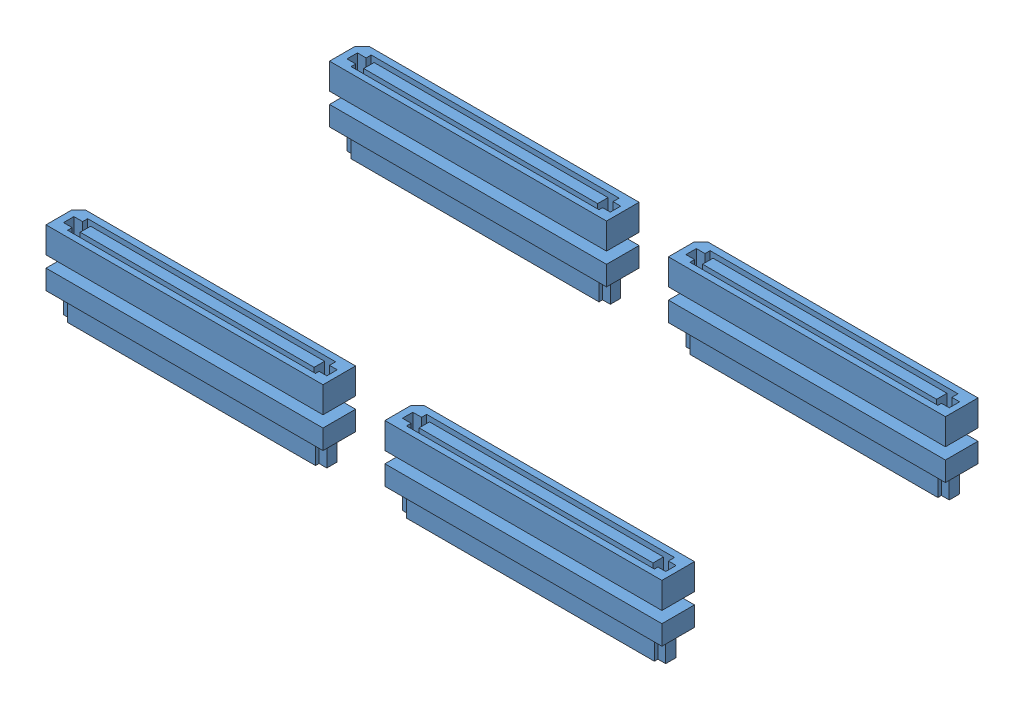
SolidWorks assembly board-interconnects.120-pin.top-SV.bottom-SV2, configuration Default. Lengths in mm.
Overall size (94.5 12.25 48.5).
4 component instances, 1 part files, 0 mates.
Components (placement in the parent):
- board-interconnects.120-pin.top-SV.bottom-SV2-5: board-interconnects.120-pin.top-SV.bottom-SV2 [Default] at origin size (42.5 12.25 5)
- board-interconnects.120-pin.top-SV.bottom-SV2-6: board-interconnects.120-pin.top-SV.bottom-SV2 [Default] at (0 0 -43.5) size (42.5 12.25 5)
- board-interconnects.120-pin.top-SV.bottom-SV2-7: board-interconnects.120-pin.top-SV.bottom-SV2 [Default] at (52 0 0) size (42.5 12.25 5)
- board-interconnects.120-pin.top-SV.bottom-SV2-8: board-interconnects.120-pin.top-SV.bottom-SV2 [Default] at (52 0 -43.5) size (42.5 12.25 5)
